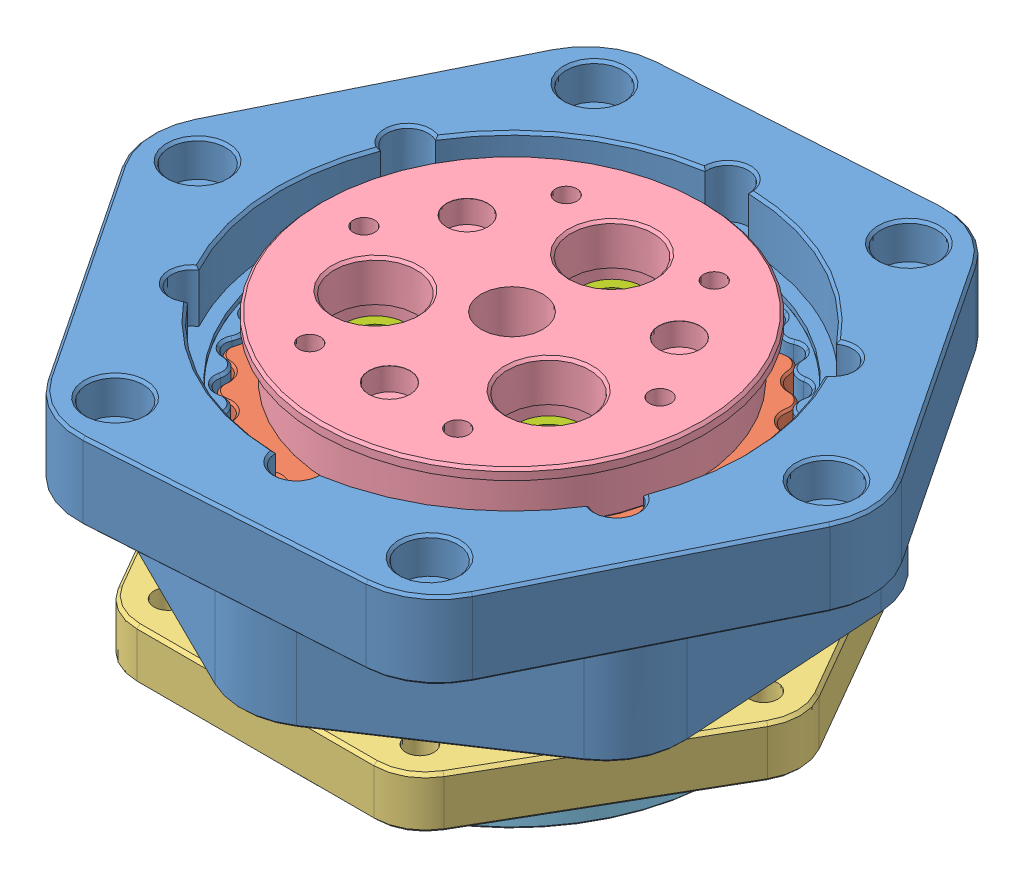
SolidWorks assembly RV Reducer, configuration Default. Lengths in mm.
Overall size (166.97 58.5 173.27).
61 component instances, 14 part files, 48 mates.
Components (placement in the parent):
- rv_reducer_basepart-1: rv_reducer_basepart [Default] at origin size (100 16 100) (hidden)
- Output Assembly-1: Output Assembly [Default] at (-0.4882 38 0.9857) x (-0.443843 0 0.896104) z (0.896104 0 0.443843) size (133.92 37 120)
- bearing-1: bearing [6814] at (0 16 0) x (0 1 0) z (0.464587 0 -0.885528) size (10 90 90) (hidden)
- bearing-2: bearing [6814] at (0 42.5 0) x (0 1 0) z (0.05853 0 0.998286) size (10 90 90) (hidden)
- Cycloidal Disk-1: Cycloidal Disk [Default] at (-1.05 36.25 -0.328) x (0.5 0 -0.866025) z (-0.866025 0 -0.5) size (79.98 7 80.05)
- Cycloidal Disk-2: Cycloidal Disk [Default] at (1.05 21.75 0.328) x (-0.5 0 0.866025) z (-0.866025 0 -0.5) size (79.98 7 80.05)
- Base Assembly-1: Base Assembly [Default] at (-2.343 -36.5096 -11.0055) size (112.38 103.5 100)
  - Base - Gear Housing-1: Base - Gear Housing [Default] at (2.343 36.5096 11.0055) size (112.38 21.91 100)
  - Base - Top Cap-1: Base - Top Cap [Default] at (2.343 74.0096 11.0055) size (75 29.5 75)
  - DIN912-M4x40-1: DIN912-M4x40 [91290A184] at (23.0269 63.6096 -0.9364) x (1 0 0) z (0 1 0) size (7 7 44.43) (hidden)
  - DIN912-M4x40-2: DIN912-M4x40 [91290A184] at (2.343 63.6096 34.8891) x (1 0 0) z (0 1 0) size (7 7 44.43) (hidden)
  - DIN912-M4x40-3: DIN912-M4x40 [91290A184] at (-18.3408 63.6096 -0.9364) x (1 0 0) z (0 1 0) size (7 7 44.43) (hidden)
  - Base - Motor Mount-1: Base - Motor Mount [Default] at (2.343 27.5096 11.0055) x (-1 0 0) z (0 0 -1) size (82 11 82)
  - NEMA23 Stepper motor-1: NEMA23 Stepper motor [Default] at (2.343 -17.4904 11.0055) x (-1 0 0) z (0 0 -1) size (56.4 65 56.4) (hidden)
  - Heat-Set Insert - m4 5.5x6mm-1: Heat-Set Insert - m4 5.5x6mm [94459A160] at (-21.227 32.0096 -12.5645) size (6.04 6.15 6.04) (hidden)
  - Heat-Set Insert - m4 5.5x6mm-2: Heat-Set Insert - m4 5.5x6mm [94459A160] at (25.913 32.0096 -12.5645) size (6.04 6.15 6.04) (hidden)
  - Heat-Set Insert - m4 5.5x6mm-3: Heat-Set Insert - m4 5.5x6mm [94459A160] at (25.913 32.0096 34.5755) size (6.04 6.15 6.04) (hidden)
  - Heat-Set Insert - m4 5.5x6mm-4: Heat-Set Insert - m4 5.5x6mm [94459A160] at (-21.227 32.0096 34.5755) size (6.04 6.15 6.04) (hidden)
  - DIN912-M4x12-1: DIN912-M4x12 [92290A154] at (25.913 26.5096 34.5755) x (1 0 0) z (0 -1 0) size (7 7 16.25) (hidden)
  - DIN912-M4x12-2: DIN912-M4x12 [92290A154] at (34.843 36.7096 -2.9945) x (1 0 0) z (0 -1 0) size (7 7 16.25) (hidden)
  - DIN912-M4x12-3: DIN912-M4x12 [92290A154] at (-30.157 36.7096 -2.9945) x (-0.837169 0 -0.546944) z (0 -1 0) size (7 7 16.25) (hidden)
  - DIN912-M4x12-4: DIN912-M4x12 [92290A154] at (-10.157 36.7096 44.0055) x (1 0 0) z (0 -1 0) size (7 7 16.25) (hidden)
  - DIN912-M4x12-5: DIN912-M4x12 [92290A154] at (14.843 36.7096 44.0055) x (1 0 0) z (0 -1 0) size (7 7 16.25) (hidden)
  - DIN912-M4x12-6: DIN912-M4x12 [92290A154] at (-21.227 26.5096 34.5755) x (-0.837169 0 -0.546944) z (0 -1 0) size (7 7 16.25) (hidden)
  - DIN912-M4x12-7: DIN912-M4x12 [92290A154] at (25.913 26.5096 -12.5645) x (1 0 0) z (0 -1 0) size (7 7 16.25) (hidden)
  - DIN912-M4x12-8: DIN912-M4x12 [92290A154] at (-21.227 26.5096 -12.5645) x (1 0 0) z (0 -1 0) size (7 7 16.25) (hidden)
- Spur Gear-2: Spur Gear [small] at (0 2 0) x (-0.907308 0 -0.420467) z (0 -1 0) size (14.83 14.76 17.06)
- Wobbler Assem-1: Wobbler Assem [Default] at (0 21 -19.5) x (0.954511 0 0.298175) z (-0.298175 0 0.954511) size (30.56 44.78 28.88)
  - Eccentric Shaft - FDM-1: Eccentric Shaft - FDM [Default] x (-1 0 0) z (0 0 -1) size (21.1 22.5 18.9)
  - Spur Gear-1: Spur Gear [Large] at (0 -9 0) x (1 0 0) z (0 1 0) size (27.81 27.81 18.06)
  - bearing-4: bearing [6701] at (0 -2 0) x (0 1 0) z (-0.777842 0 -0.62846) size (4 18 18) (hidden)
  - bearing-3: bearing [6701] at (0 18 0) x (0 1 0) z (-0.917921 0 0.396763) size (4 18 18) (hidden)
  - bearing-2: bearing [6703] at (-1.1 11.75 0) x (0 1 0) z (0.239406 0 0.97092) size (4 23 23) (hidden)
  - bearing-1: bearing [6703] at (1.1 4.25 0) x (0 1 0) z (0.953192 0 0.302367) size (4 23 23) (hidden)
  - DIN912-M4x40-1: DIN912-M4x40 [91290A184] at (0 -2.4 0) x (0.137096 0 -0.990558) z (0 1 0) size (7 7 44.43) (hidden)
  - DIN985-M4-Locknut-1: DIN985-M4-Locknut [90576A103] at (0 -15.5 0) x (0.866025 0 0.5) z (0 -1 0) size (7 8.08 5.09) (hidden)
- Wobbler Assem-2: Wobbler Assem [Default] at (16.8875 21 9.75) x (0.954511 0 0.298175) z (-0.298175 0 0.954511) size (30.56 44.78 28.88)
  - Eccentric Shaft - FDM-1: Eccentric Shaft - FDM [Default] x (-1 0 0) z (0 0 -1) size (21.1 22.5 18.9)
  - Spur Gear-1: Spur Gear [Large] at (0 -9 0) x (1 0 0) z (0 1 0) size (27.81 27.81 18.06)
  - bearing-4: bearing [6701] at (0 -2 0) x (0 1 0) z (-0.777842 0 -0.62846) size (4 18 18) (hidden)
  - bearing-3: bearing [6701] at (0 18 0) x (0 1 0) z (-0.917921 0 0.396763) size (4 18 18) (hidden)
  - bearing-2: bearing [6703] at (-1.1 11.75 0) x (0 1 0) z (0.239406 0 0.97092) size (4 23 23) (hidden)
  - bearing-1: bearing [6703] at (1.1 4.25 0) x (0 1 0) z (0.953192 0 0.302367) size (4 23 23) (hidden)
  - DIN912-M4x40-1: DIN912-M4x40 [91290A184] at (0 -2.4 0) x (0.137096 0 -0.990558) z (0 1 0) size (7 7 44.43) (hidden)
  - DIN985-M4-Locknut-1: DIN985-M4-Locknut [90576A103] at (0 -15.5 0) x (0.866025 0 0.5) z (0 -1 0) size (7 8.08 5.09) (hidden)
- Wobbler Assem-4: Wobbler Assem [Default] at (-16.8875 21 9.75) x (0.954511 0 0.298175) z (-0.298175 0 0.954511) size (30.56 44.78 28.88)
  - Eccentric Shaft - FDM-1: Eccentric Shaft - FDM [Default] x (-1 0 0) z (0 0 -1) size (21.1 22.5 18.9)
  - Spur Gear-1: Spur Gear [Large] at (0 -9 0) x (1 0 0) z (0 1 0) size (27.81 27.81 18.06)
  - bearing-4: bearing [6701] at (0 -2 0) x (0 1 0) z (-0.777842 0 -0.62846) size (4 18 18) (hidden)
  - bearing-3: bearing [6701] at (0 18 0) x (0 1 0) z (-0.917921 0 0.396763) size (4 18 18) (hidden)
  - bearing-2: bearing [6703] at (-1.1 11.75 0) x (0 1 0) z (0.239406 0 0.97092) size (4 23 23) (hidden)
  - bearing-1: bearing [6703] at (1.1 4.25 0) x (0 1 0) z (0.953192 0 0.302367) size (4 23 23) (hidden)
  - DIN912-M4x40-1: DIN912-M4x40 [91290A184] at (0 -2.4 0) x (0.137096 0 -0.990558) z (0 1 0) size (7 7 44.43) (hidden)
  - DIN985-M4-Locknut-1: DIN985-M4-Locknut [90576A103] at (0 -15.5 0) x (0.866025 0 0.5) z (0 -1 0) size (7 8.08 5.09) (hidden)
- Heat-Set Insert - m4 5.5x6mm-1: Heat-Set Insert - m4 5.5x6mm [94459A160] at (0 14.4226 23.8837) x (-0.837169 0 -0.546944) z (-0.546944 0 0.837169) size (6.04 6.15 6.04) (hidden)
- Heat-Set Insert - m4 5.5x6mm-2: Heat-Set Insert - m4 5.5x6mm [94459A160] at (32.5 3 -14) x (-0.837169 0 -0.546944) z (-0.546944 0 0.837169) size (6.04 6.15 6.04) (hidden)
- Heat-Set Insert - m4 5.5x6mm-3: Heat-Set Insert - m4 5.5x6mm [94459A160] at (-20.6839 14.4226 -11.9418) x (-0.837169 0 -0.546944) z (-0.546944 0 0.837169) size (6.04 6.15 6.04) (hidden)
- Heat-Set Insert - m4 5.5x6mm-4: Heat-Set Insert - m4 5.5x6mm [94459A160] at (-32.5 3 -14) x (-0.837169 0 -0.546944) z (-0.546944 0 0.837169) size (6.04 6.15 6.04) (hidden)
- Heat-Set Insert - m4 5.5x6mm-5: Heat-Set Insert - m4 5.5x6mm [94459A160] at (-12.5 3 33) x (-0.837169 0 -0.546944) z (-0.546944 0 0.837169) size (6.04 6.15 6.04) (hidden)
- Heat-Set Insert - m4 5.5x6mm-6: Heat-Set Insert - m4 5.5x6mm [94459A160] at (20.6839 14.4226 -11.9418) x (-0.837169 0 -0.546944) z (-0.546944 0 0.837169) size (6.04 6.15 6.04) (hidden)
- Heat-Set Insert - m4 5.5x6mm-7: Heat-Set Insert - m4 5.5x6mm [94459A160] at (12.5 3 33) x (-0.837169 0 -0.546944) z (-0.546944 0 0.837169) size (6.04 6.15 6.04) (hidden)
Mates (geometry in assembly coordinates):
- Concentric58: concentric anti-aligned: cylinder of Cycloidal Disk-2 through (1.05 28.75 -19.172) axis (0 -1 0) radius 11.5; cylinder of Wobbler Assem-1/bearing-1 through (1.05 31.7312 -19.172) axis (0 1 0) radius 11.5
- Coincident40: coincident anti-aligned: plane of Cycloidal Disk-2 through (1.05 23.25 -19.172) normal (0 1 0); plane of Wobbler Assem-1/bearing-1 through (-5.1939 23.25 -10.2376) normal (0 -1 0)
- Coincident41: coincident anti-aligned: plane of Cycloidal Disk-1 through (-1.05 34.75 -19.828) normal (0 -1 0); plane of Wobbler Assem-1/bearing-2 through (-11.9297 34.75 -20.4928) normal (0 1 0)
- Concentric59: concentric aligned: cylinder of Cycloidal Disk-1 through (-1.05 29.25 -19.828) axis (0 1 0) radius 11.5; cylinder of Wobbler Assem-1/bearing-2 through (-1.05 39.2312 -19.828) axis (0 1 0) radius 11.5
- Concentric61: concentric anti-aligned: cylinder of Cycloidal Disk-2 through (17.9375 28.75 10.078) axis (0 -1 0) radius 11.5; cylinder of Wobbler Assem-2/bearing-1 through (17.9375 31.7312 10.078) axis (0 1 0) radius 11.5
- Concentric62: concentric aligned: cylinder of Cycloidal Disk-1 through (15.8375 29.25 9.422) axis (0 1 0) radius 11.5; cylinder of Wobbler Assem-2/bearing-2 through (15.8375 39.2312 9.422) axis (0 1 0) radius 11.5
- Concentric64: concentric anti-aligned: cylinder of Cycloidal Disk-2 through (-15.8375 28.75 10.078) axis (0 -1 0) radius 11.5; cylinder of Wobbler Assem-4/bearing-1 through (-15.8375 31.7312 10.078) axis (0 1 0) radius 11.5
- Concentric65: concentric aligned: cylinder of Cycloidal Disk-1 through (-17.9375 29.25 9.422) axis (0 1 0) radius 11.5; cylinder of Wobbler Assem-4/bearing-2 through (-17.9375 39.2312 9.422) axis (0 1 0) radius 11.5
- Coincident42: coincident aligned: plane of Wobbler Assem-1/Eccentric Shaft - FDM-1 through (5.7271 41 -17.7109) normal (0 1 0); plane of Wobbler Assem-4/Eccentric Shaft - FDM-1 through (-11.1604 41 11.5391) normal (0 1 0)
- Coincident43: coincident aligned: plane of Wobbler Assem-1/Eccentric Shaft - FDM-1 through (5.7271 41 -17.7109) normal (0 1 0); plane of Wobbler Assem-2/Eccentric Shaft - FDM-1 through (22.6146 41 11.5391) normal (0 1 0)
- GearMate8: gear = 12.99 : 25.98 mm: circle of wobbler-1/Spur Gear-1; circle of Spur Gear-2
- Distance1: distance = 2 mm anti-aligned: plane of Base Assembly-1/Base - Gear Housing-1 through (0 14 0) normal (0 -1 0); plane of Spur Gear-2 through (0 12 0) normal (0 1 0)
- Concentric74: concentric aligned: cylinder of Base Assembly-1/Base - Gear Housing-1 through (0 107.4005 0) axis (0 -1 0) radius 20; cylinder of Spur Gear-2 through (0 12.0617 0) axis (0 -1 0) radius 3.175
- Coincident57: coincident anti-aligned: plane of Base Assembly-1/Base - Gear Housing-1 through (0 17 0) normal (0 1 0); plane of Wobbler Assem-1/bearing-4 through (6.9872 17 -24.1626) normal (0 -1 0)
- Concentric76: concentric anti-aligned: cylinder of Base Assembly-1/Base - Gear Housing-1 through (0 21 -19.5) axis (0 -1 0) radius 9; cylinder of Wobbler Assem-1/bearing-4 through (0 25.4812 -19.5) axis (0 1 0) radius 9
- Concentric77: concentric anti-aligned: cylinder of Base Assembly-1/Base - Gear Housing-1 through (16.8875 46.4558 9.75) axis (0 -1 0) radius 8; cylinder of Wobbler Assem-2/bearing-4 through (16.8875 25.4812 9.75) axis (0 1 0) radius 9
- Concentric78: concentric anti-aligned: cylinder of Base Assembly-1/Base - Gear Housing-1 through (-16.8875 46.4558 9.75) axis (0 -1 0) radius 8; cylinder of Wobbler Assem-4/bearing-4 through (-16.8875 25.4812 9.75) axis (0 1 0) radius 9
- Coincident59: coincident aligned: plane of Base Assembly-1/Base - Gear Housing-1 through (0 0 0) normal (1 0 0)
- Coincident60: coincident aligned: plane of Base Assembly-1/Base - Gear Housing-1 through (0 0 0) normal (0 0 1)
- Coincident61: coincident aligned: plane of Base Assembly-1/Base - Gear Housing-1 through (0 0 0) normal (0 1 0)
- Concentric79: concentric aligned: cylinder of Wobbler Assem-2/bearing-3 through (16.8875 45.4812 9.75) axis (0 1 0) radius 9; cylinder of Base Assembly-1/Base - Top Cap-1 through (16.8875 12.0442 9.75) axis (0 1 0) radius 8
- Concentric80: concentric aligned: cylinder of Wobbler Assem-1/bearing-3 through (0 45.4812 -19.5) axis (0 1 0) radius 9; cylinder of Base Assembly-1/Base - Top Cap-1 through (0 12.0442 -19.5) axis (0 1 0) radius 8
- Concentric81: concentric aligned: cylinder of Wobbler Assem-4/bearing-3 through (-16.8875 45.4812 9.75) axis (0 1 0) radius 9; cylinder of Base Assembly-1/Base - Top Cap-1 through (-16.8875 12.0442 9.75) axis (0 1 0) radius 8
- Concentric83: concentric aligned: cylinder of Base Assembly-1/Base - Motor Mount-1 through (0 0 0) axis (0 -1 0) radius 41
- Coincident65: coincident anti-aligned: plane of Base Assembly-1/Base - Motor Mount-1 through (0 -9 0) normal (0 0 -1)
- Concentric69: concentric anti-aligned: cylinder of Output Assembly-1 through (0 38 0) axis (0 -1 0) radius 45; cylinder of bearing-1 through (0 22.4812 0) axis (0 1 0) radius 45
- Coincident48: coincident anti-aligned: plane of Output Assembly-1 through (0 21 0) normal (0 -1 0); plane of bearing-1 through (38.0777 21 19.9772) normal (0 1 0)
- Concentric84: concentric anti-aligned: cylinder of Base Assembly-1/Base - Gear Housing-1 through (0 21 0) axis (0 -1 0) radius 35; cylinder of bearing-1 through (0 22.4812 0) axis (0 1 0) radius 35
- Coincident66: coincident anti-aligned: plane of Base Assembly-1/Base - Gear Housing-1 through (0 11 0) normal (0 1 0); plane of bearing-1 through (30.9935 11 16.2605) normal (0 -1 0)
- GearMate12: gear = 28 : 1 mm: unknown of Wobbler Assem-2/bearing-3; cylinder of bearing-2 through (0 48.9812 0) axis (0 1 0) radius 43
- Coincident67: coincident anti-aligned: plane of bearing-2 through (-34.94 47.5 2.0485) normal (0 1 0); plane of Base Assembly-1/Base - Top Cap-1 through (0 47.5 0) normal (0 -1 0)
- Coincident68: coincident aligned: plane of Base Assembly-1/Base - Gear Housing-1; plane of Heat-Set Insert - m4 5.5x6mm-1 through (-2.3022 17.4226 22.3796) normal (0 1 0)
- Concentric85: concentric anti-aligned: cylinder of Base Assembly-1/Base - Gear Housing-1 through (0 18 23.8837) axis (0 -1 0) radius 2.75; cylinder of Heat-Set Insert - m4 5.5x6mm-1 through (0 17.4226 23.8837) axis (0 1 0) radius 2.75
- Coincident70: coincident aligned: plane of Base Assembly-1/Base - Gear Housing-1; plane of Heat-Set Insert - m4 5.5x6mm-6 through (18.3816 17.4226 -13.4459) normal (0 1 0)
- Coincident71: coincident aligned: plane of Base Assembly-1/Base - Gear Housing-1; plane of Heat-Set Insert - m4 5.5x6mm-3 through (-22.9861 17.4226 -13.4459) normal (0 1 0)
- Concentric86: concentric anti-aligned: cylinder of Base Assembly-1/Base - Gear Housing-1 through (-20.6839 18 -11.9418) axis (0 -1 0) radius 2.75; cylinder of Heat-Set Insert - m4 5.5x6mm-3 through (-20.6839 17.4226 -11.9418) axis (0 1 0) radius 2.75
- Concentric87: concentric anti-aligned: cylinder of Base Assembly-1/Base - Gear Housing-1 through (20.6839 18 -11.9418) axis (0 -1 0) radius 2.75; cylinder of Heat-Set Insert - m4 5.5x6mm-6 through (20.6839 17.4226 -11.9418) axis (0 1 0) radius 2.75
- Coincident72: coincident aligned: plane of Base Assembly-1/Base - Gear Housing-1 through (0 0 0) normal (0 -1 0); plane of Heat-Set Insert - m4 5.5x6mm-4 through (-35.0115 0 -15.6408) normal (0 -1 0)
- Coincident73: coincident aligned: plane of Base Assembly-1/Base - Gear Housing-1 through (0 0 0) normal (0 -1 0); plane of Heat-Set Insert - m4 5.5x6mm-5 through (-15.0115 0 31.3592) normal (0 -1 0)
- Coincident74: coincident aligned: plane of Base Assembly-1/Base - Gear Housing-1 through (0 0 0) normal (0 -1 0); plane of Heat-Set Insert - m4 5.5x6mm-2 through (29.9885 0 -15.6408) normal (0 -1 0)
- Coincident75: coincident aligned: plane of Base Assembly-1/Base - Gear Housing-1 through (0 0 0) normal (0 -1 0); plane of Heat-Set Insert - m4 5.5x6mm-7 through (9.9885 0 31.3592) normal (0 -1 0)
- Concentric88: concentric anti-aligned: cylinder of Base Assembly-1/Base - Gear Housing-1 through (32.5 7 -14) axis (0 -1 0) radius 2.75; cylinder of Heat-Set Insert - m4 5.5x6mm-2 through (32.5 6 -14) axis (0 1 0) radius 2.75
- Concentric89: concentric anti-aligned: cylinder of Base Assembly-1/Base - Gear Housing-1 through (12.5 7 33) axis (0 -1 0) radius 2.75; cylinder of Heat-Set Insert - m4 5.5x6mm-7 through (12.5 6 33) axis (0 1 0) radius 2.75
- Concentric90: concentric anti-aligned: cylinder of Base Assembly-1/Base - Gear Housing-1 through (-12.5 7 33) axis (0 -1 0) radius 2.75; cylinder of Heat-Set Insert - m4 5.5x6mm-5 through (-12.5 6 33) axis (0 1 0) radius 2.75
- Concentric91: concentric anti-aligned: cylinder of Base Assembly-1/Base - Gear Housing-1 through (-32.5 7 -14) axis (0 -1 0) radius 2.75; cylinder of Heat-Set Insert - m4 5.5x6mm-4 through (-32.5 6 -14) axis (0 1 0) radius 2.75
- Concentric104: concentric anti-aligned: cylinder of Output Assembly-1 through (0 38 0) axis (0 -1 0) radius 45; cylinder of bearing-2 through (0 48.9812 0) axis (0 1 0) radius 45
- Distance2: distance = 1.5 mm: plane of Output Assembly-1 through (0 48 0) normal (0 1 0); plane of Base Assembly-1/Base - Top Cap-1 through (0 49.5 0) normal (0 1 0)
- Concentric105: concentric anti-aligned: cylinder of Output Assembly-1 through (0 21 0) axis (0 1 0) radius 45; cylinder of Base Assembly-1/Base - Top Cap-1 through (0 49.5 0) axis (0 -1 0) radius 35
